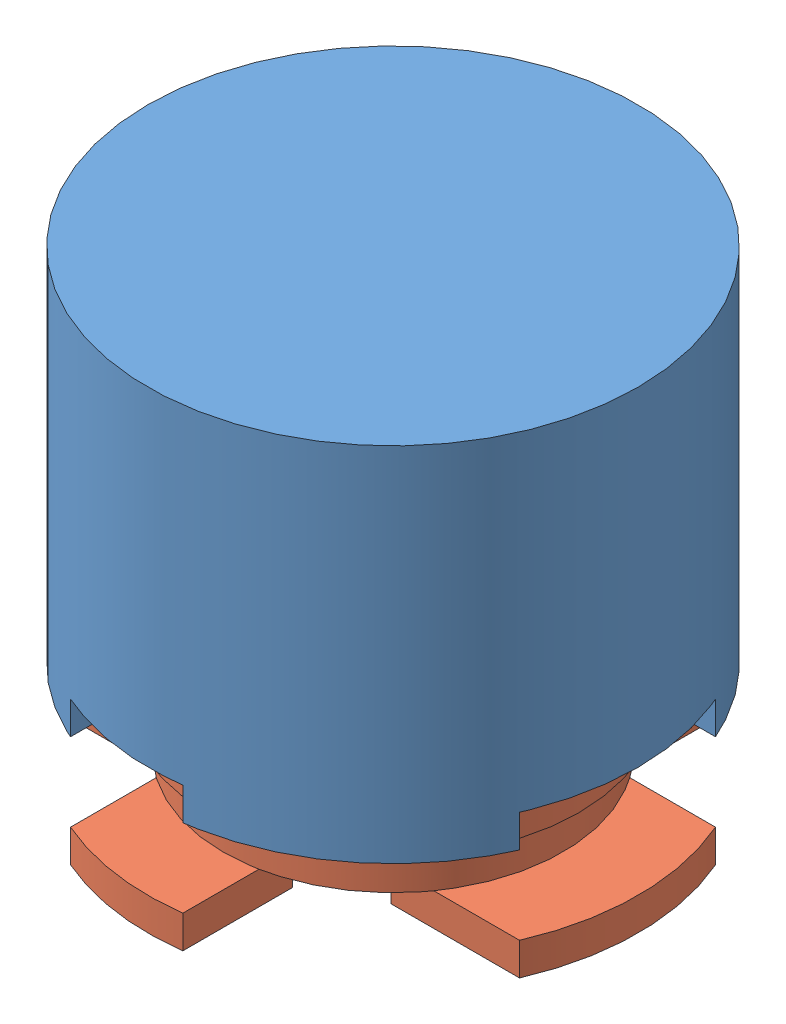
SolidWorks assembly Assem4, configuration Default. Lengths in mm.
Overall size (48.27 51.8 47.62).
2 component instances, 2 part files, 3 mates.
Components (placement in the parent):
- Inner Mold Bottom-1: Inner Mold Bottom [Default] at origin size (47.62 35.18 47.62)
- Inner Mold Top-1: Inner Mold Top [Default] at (0 -10.7805 0) size (48.27 36.25 47.62)
Mates (geometry in assembly coordinates):
- Concentric1: concentric anti-aligned: cylinder of Inner Mold Bottom-1 through (0 12.2809 0) axis (0 1 0) radius 23.8125; cylinder of Inner Mold Top-1 through (0 -10.7805 0) axis (0 -1 0) radius 16.51
- Coincident1: coincident anti-aligned: plane of Inner Mold Bottom-1 through (3.175 -19.7231 9.525) normal (0 0 -1); plane of Inner Mold Top-1 through (3.175 -30.5036 9.525) normal (0 0 1)
- Coincident2: coincident anti-aligned: plane of Inner Mold Bottom-1 through (0 -19.7231 0) normal (0 -1 0); plane of Inner Mold Bottom-1 through (-20.6375 -19.7231 0) normal (0 1 0)
